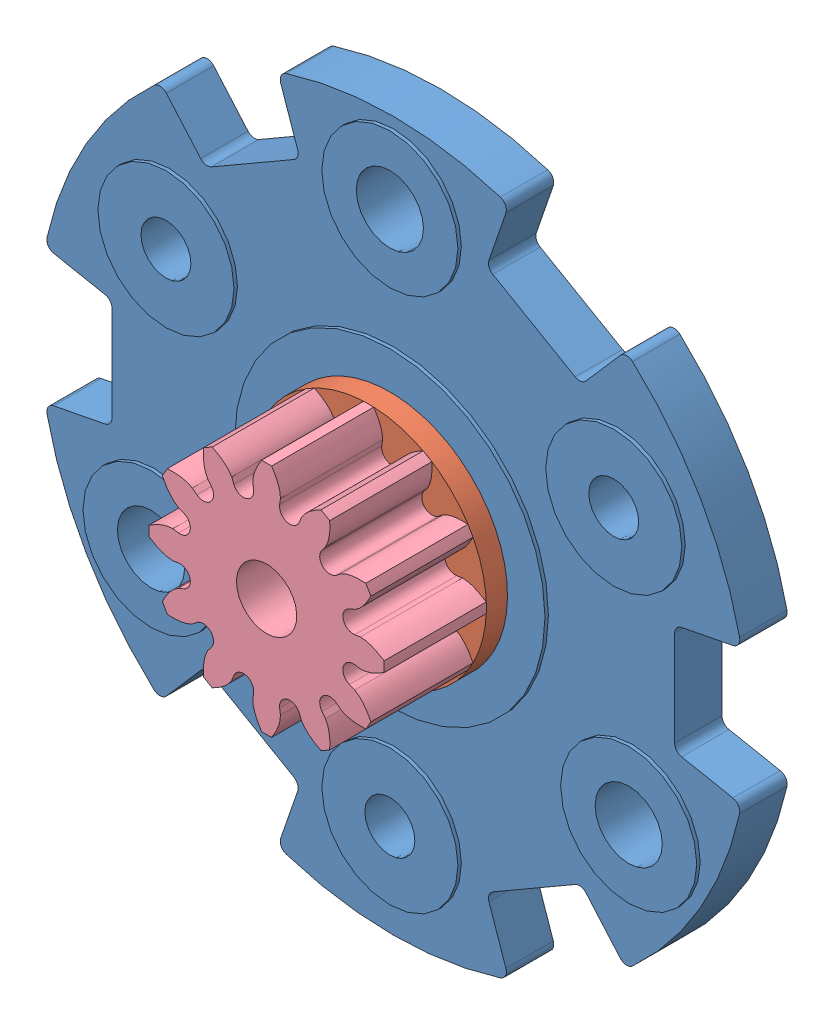
SolidWorks assembly OrangeDriveDiskCut, configuration Default. Lengths in mm.
Overall size (20.43 20.9 6.64).
5 component instances, 4 part files, 3 mates.
Components (placement in the parent):
- OrangeDriveDisk-1: OrangeDriveDisk [Default] at (8.2689 12.5714 14.6704) size (20.43 20.9 2.98)
- OrangeSunGear-1: OrangeSunGear [Default] at (8.2689 12.5714 13.1591) x (0 1 0) z (0 0 1) size (9.6 9.6 6.64)
  - OrangeIntermediaryPlate-1: OrangeIntermediaryPlate [Default] at (0 0 3.0099) x (0.83755 -0.546361 0) z (0 0 1) size (6.93 6.93 0.62)
  - OrangeSpurSmall-2: OrangeSpurSmall [Default] at origin size (5.78 5.84 3.01)
  - OrangeSpurLarge-2: OrangeSpurLarge [Default] at (0 0 3.6322) size (6.93 6.93 3.01)
Mates (geometry in assembly coordinates):
- Concentric1: concentric aligned: cylinder of OrangeDriveDisk-1 through (8.2689 12.5714 16.169) axis (0 0 -1) radius 4.572; cylinder of OrangeSunGear-1/OrangeSpurSmall-2 through (8.2689 12.5714 16.169) axis (0 0 -1) radius 0.889
- Coincident1: coincident anti-aligned: plane of OrangeDriveDisk-1 through (8.2689 12.5714 16.169) normal (0 0 1); plane of OrangeSunGear-1/OrangeIntermediaryPlate-1 through (8.2689 12.5714 16.169) normal (0 0 -1)
- Parallel1: parallel aligned: plane of OrangeSunGear-1/OrangeSpurSmall-2; plane of assembly through (0 0 0) normal (0 1 0)
